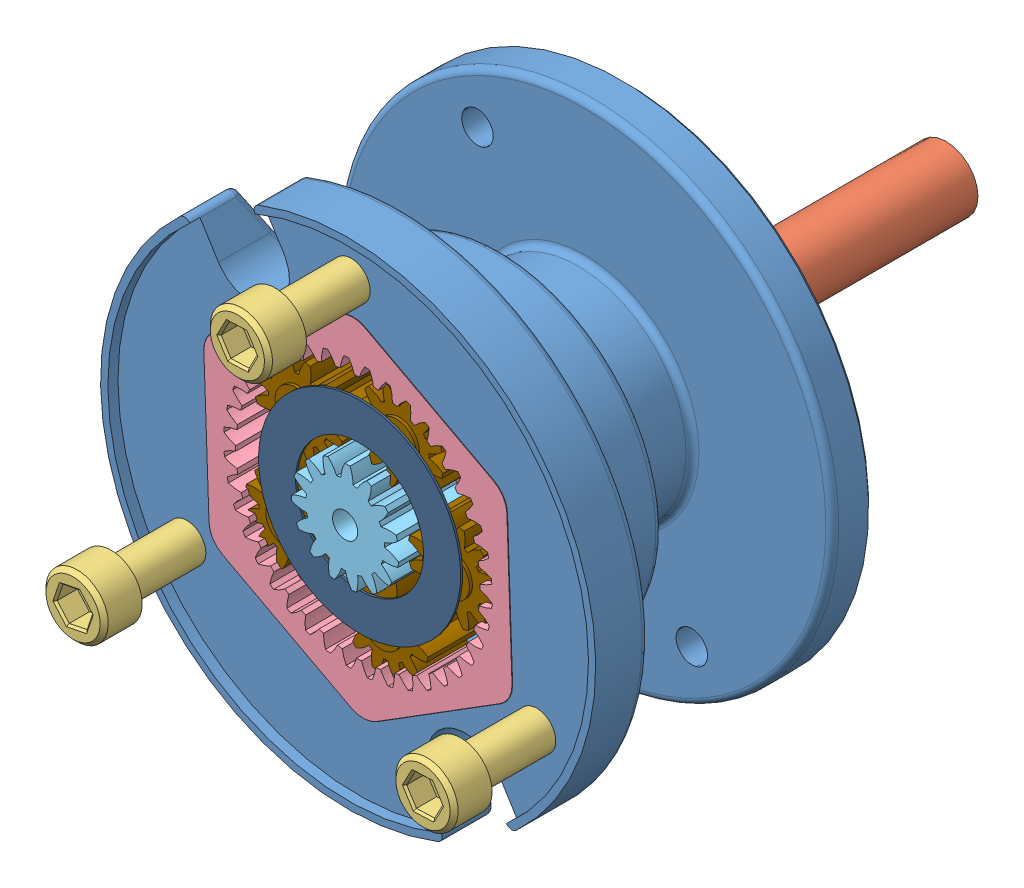
SolidWorks assembly AMPlanetary2, configuration Default. Lengths in mm.
Overall size (85.76 85.76 88.18).
25 component instances, 12 part files, 0 mates.
Components (placement in the parent):
- housing-1: housing [Default] at (0 0 1.3508) x (0.530131 -0.847916 0) z (-0.847916 -0.530131 0) size (62.23 38.74 62.23)
- Universal_cap-1: Universal_cap [Default] at (0 0 44.4038) x (-0.847916 -0.530131 0) z (0.530131 -0.847916 0) size (60.32 9.53 60.32) (hidden)
- shaft-1: shaft [Default] at (0 0 27.35) x (0.858633 0.512591 0) z (0 0 1) size (28.57 28.57 66.35)
- 10-32x0625_shcs-1: 10-32x0625_shcs [Default] at (-21.5371 -13.4653 49.179) x (-0.194995 0.980804 0) z (0.980804 0.194995 0) size (7.82 20.65 7.82)
- 10-32x0625_shcs-2: 10-32x0625_shcs [Default] at (22.4298 -11.919 49.179) x (-0.884425 0.466682 0) z (0.466682 0.884425 0) size (7.82 20.65 7.82)
- 10-32x0625_shcs-3: 10-32x0625_shcs [Default] at (-0.8928 25.3843 49.179) x (-0.884425 0.466682 0) z (0.466682 0.884425 0) size (7.82 20.65 7.82)
- ring_gear-1: ring_gear [Default] at (0 0 34.9192) x (-0.847916 -0.530131 0) z (0 0 1) size (43.01 38.1 7)
- sun_gear-1: sun_gear [Default] at (0 0 36.525) x (0.89496 -0.446147 0) z (0 0 1) size (13.47 13.43 9.57)
- 90295A160_nylon_washer-1: 90295A160_nylon_washer [Default] at (0 0 21) x (-0.995317 0.096661 0) z (-0.096661 -0.995317 0) size (19.05 1.32 19.05)
- 90295A160_nylon_washer-2: 90295A160_nylon_washer [Default] at (0 0 8.6208) x (0.616153 -0.787627 0) z (-0.787627 -0.616153 0) size (19.05 1.32 19.05)
- 90295A160_nylon_washer-3: 90295A160_nylon_washer [Default] at (0 0 9.9416) x (0.658273 -0.752779 0) z (-0.752779 -0.658273 0) size (19.05 1.32 19.05)
- 90295A160_nylon_washer-4: 90295A160_nylon_washer [Default] at (0 0 11.2624) x (0.658273 -0.752779 0) z (-0.752779 -0.658273 0) size (19.05 1.32 19.05)
- 8mmx22mmx7mm_bearing-1: 8mmx22mmx7mm_bearing [Default] at (0 0 19.6792) x (-0.788017 -0.615654 0) z (0.615654 -0.788017 0) size (22 7 22)
- 8mmx19mmx6mm_bearing-1: 8mmx19mmx6mm_bearing [Default] at (0 0 2.6208) x (-0.978933 -0.204182 0) z (-0.204182 0.978933 0) size (19 6 19)
- planet_gear2-1: planet_gear2 [Default] at (-8.3264 7.2798 27.731) x (0.671332 0.741157 0) z (0 0 -1) size (11.11 11.11 7.11)
- planet_gear2-2: planet_gear2 [Default] at (4.3505 10.1684 27.731) x (0.671332 0.741157 0) z (0 0 -1) size (11.11 11.11 7.11)
- planet_gear2-3: planet_gear2 [Default] at (11.0151 -0.9954 27.731) x (0.671332 0.741157 0) z (0 0 -1) size (11.11 11.11 7.11)
- planet_gear2-4: planet_gear2 [Default] at (-9.4965 -5.6693 27.731) x (0.671332 0.741157 0) z (0 0 -1) size (11.11 11.11 7.11)
- planet_gear2-5: planet_gear2 [Default] at (2.4572 -10.7836 27.731) x (0.671332 0.741157 0) z (0 0 -1) size (11.11 11.11 7.11)
- shim010-1: shim010 [Default] at (0 0 34.462) x (0.798455 -0.602055 0) z (-0.602055 -0.798455 0) size (25.4 0.25 25.4)
- planet_pin-1: planet_pin [Default] at (-8.3264 7.2798 21) x (-0.341349 0.939937 0) z (0 0 1) size (3.17 3.17 12.7)
- planet_pin-2: planet_pin [Default] at (2.4572 -10.7836 21) x (-0.276324 -0.961065 0) z (0 0 1) size (3.17 3.17 12.7)
- planet_pin-3: planet_pin [Default] at (11.0151 -0.9954 21) x (0.828638 -0.559785 0) z (0 0 1) size (3.17 3.17 12.7)
- planet_pin-4: planet_pin [Default] at (4.3505 10.1684 21) x (-0.78845 -0.615099 0) z (0 0 1) size (3.17 3.17 12.7)
- planet_pin-5: planet_pin [Default] at (-9.4965 -5.6693 21) x (0.999415 0.034186 0) z (0 0 1) size (3.17 3.17 12.7)
